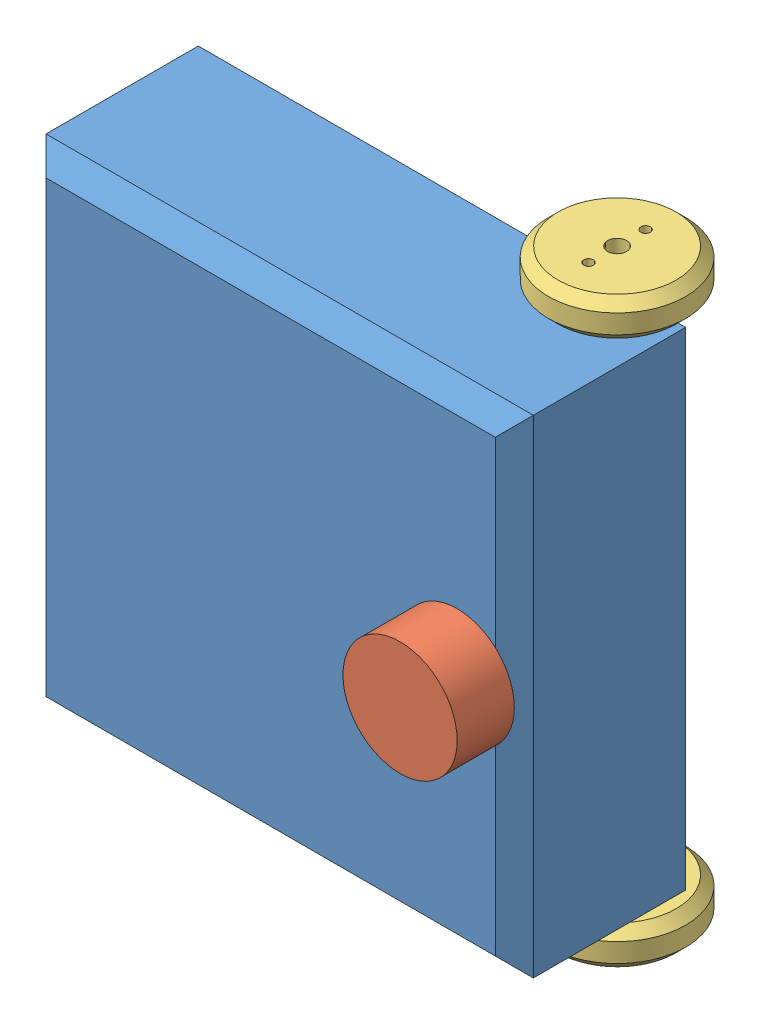
SolidWorks assembly minibot, configuration 預設. Lengths in mm.
Overall size (262 306 150).
5 component instances, 4 part files, 8 mates.
Components (placement in the parent):
- base-1: base [預設] at (-28.3626 -207.6708 150.7249) size (256 256 100)
- laser-1: laser [預設] at (69.6374 -207.6708 250.7249) size (60 60 30)
- wheel-1: wheel [預設] at (69.6374 -340.6708 166.7249) x (1 0 0) z (0 -1 0) size (72 72 20)
- wheel-2: wheel [預設] at (69.6374 -54.6708 166.7249) x (1 0 0) z (0 -1 0) size (72 72 20)
- cir-1: cir [預設] at (-96.3626 -207.6708 150.7249) size (40 40 20)
Mates (geometry in assembly coordinates):
- 重合/共線/共點1: coincident anti-aligned: plane of base-1 through (-28.3626 -207.6708 150.7249) normal (0 0 -1); plane of cir-1 through (-96.3626 -207.6708 150.7249) normal (0 0 1)
- 重合/共線/共點3: coincident anti-aligned: circle of cir-1; circle of assembly
- 同軸心1: concentric anti-aligned: cylinder of base-1 through (69.6374 -79.6708 166.7249) axis (0 -1 0) radius 5; cylinder of wheel-1 through (69.6374 -360.6708 166.7249) axis (0 1 0) radius 5
- 平行相距2: distance = 5 mm anti-aligned: plane of wheel-1 through (69.6374 -340.6708 166.7249) normal (0 1 0); plane of base-1 through (-156.3626 -335.6708 250.7249) normal (0 -1 0)
- 同軸心2: concentric anti-aligned: cylinder of base-1 through (69.6374 -79.6708 166.7249) axis (0 -1 0) radius 5; cylinder of wheel-2 through (69.6374 -74.6708 166.7249) axis (0 1 0) radius 5
- 平行相距1: distance = 5 mm anti-aligned: plane of base-1 through (-156.3626 -79.6708 250.7249) normal (0 1 0); plane of wheel-2 through (69.6374 -74.6708 166.7249) normal (0 -1 0)
- 重合/共線/共點5: coincident anti-aligned: plane of base-1 through (-28.3626 -207.6708 250.7249) normal (0 0 1); plane of laser-1 through (69.6374 -207.6708 250.7249) normal (0 0 -1)
- 同軸心3: concentric aligned: circle of laser-1; circle of assembly
